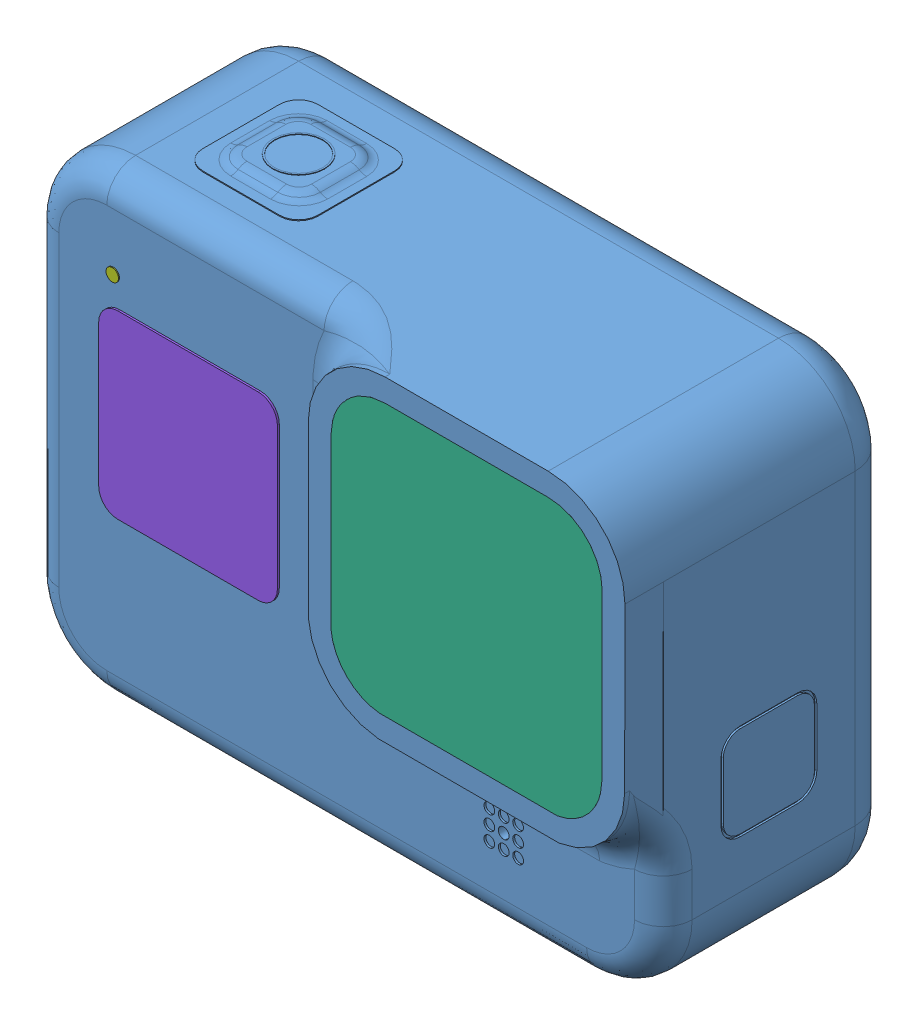
SolidWorks assembly Gopro , configuration Default. Lengths in mm.
Overall size (69.46 51.52 28.1).
9 component instances, 8 part files, 0 mates.
Components (placement in the parent):
- Gopro .step-1: Gopro .step [Default] at origin size (69.46 51.52 28.1)
  - Main.step-1: Main.step [Default] at origin size (69.46 51.52 28)
  - Plus holder.step-1: Plus holder.step [Default] at origin size (8 2.5 13.5)
  - screen.step-1: screen.step [Default] at origin size (56 38 0.1)
  - Clip 2.step-1: Clip 2.step [Default] at (-0.1783 -0.0227 0) x (0.999969 0.007874 0) z (0 0 1) size (18.8 2.2 13.09)
  - Clip 1.step-1: Clip 1.step [Default] at (0.7081 -0.1473 0) x (0.999509 -0.031319 0) z (0 0 1) size (18.8 2.2 13.09)
  - Lens guard glass.step-1: Lens guard glass.step [Default] at origin size (28.27 28.27 0.5)
  - Red light REAR.step-1: Red light REAR.step [Default] at origin size (1.3 1.3 0.1)
  - Rear screen .step-1: Rear screen .step [Default] at origin size (18.62 18.82 0.2)
